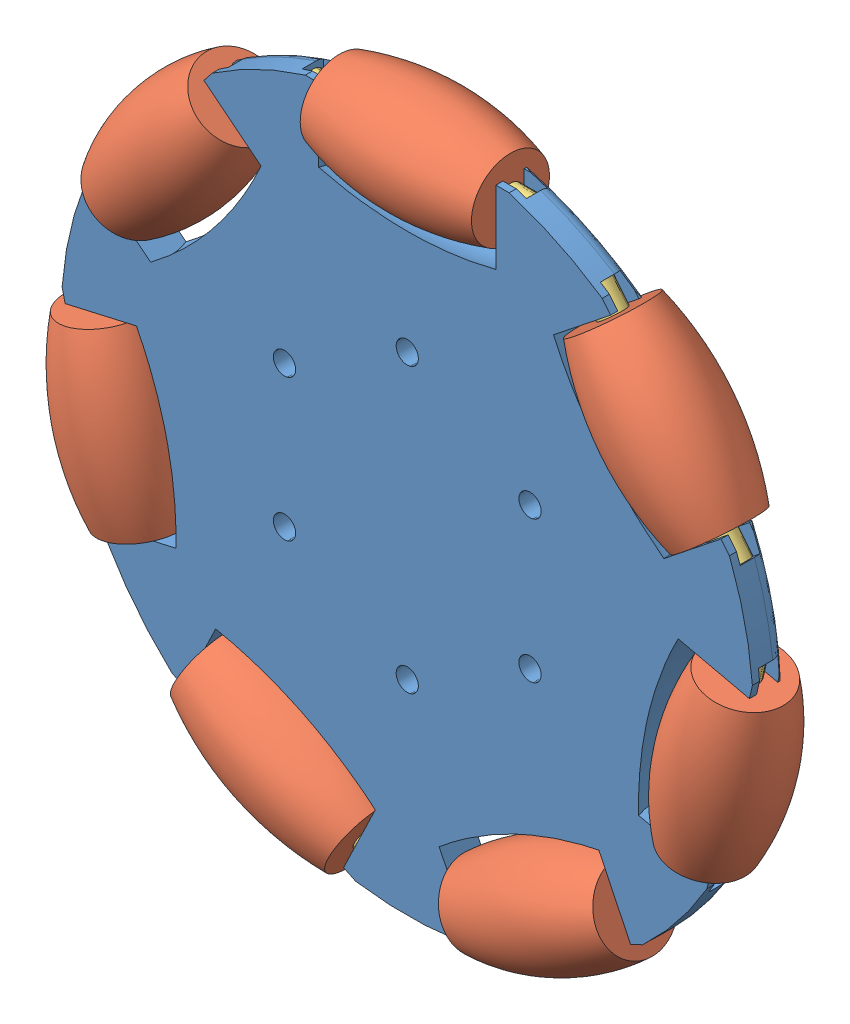
SolidWorks assembly OmniRueda, configuration Default. Lengths in mm.
Overall size (171.23 164.9 32.77).
15 component instances, 3 part files, 21 mates.
Components (placement in the parent):
- base1-1: base1 [Default] at (21.7624 30.7176 48.3759) size (155.19 151.79 15.2)
- tambor-1: tambor [Default] at (21.7309 100.0125 48.3759) size (38.41 23.31 23.31)
- tambor-2: tambor [Default] at (75.8785 73.9985 48.3759) x (0.62349 -0.781831 0) z (0.006132 0.00489 0.999969) size (38.41 23.31 23.31)
- tambor-3: tambor [Default] at (-32.3241 74.0356 48.3759) x (0.62349 0.781831 0) z (-0.451651 0.36018 0.816261) size (38.41 23.31 23.31)
- tambor-4: tambor [Default] at (89.32 15.2982 48.3759) x (0.222521 0.974928 0) z (-0.021105 0.004817 0.999766) size (38.41 23.31 23.31)
- tambor-5: tambor [Default] at (-45.7853 15.2549 48.3759) x (0.222521 -0.974928 0) z (-0.760422 -0.173561 0.625808) size (38.41 23.31 23.31)
- tambor-6: tambor [Default] at (51.6132 -31.8186 48.3759) x (0.900969 0.433884 0) z (-0.125061 0.259692 0.957559) size (38.41 23.31 23.31)
- tambor-7: tambor [Default] at (-8.5258 -31.6079 48.3759) x (0.900969 -0.433884 0) z (0.089476 0.185799 0.978505) size (38.41 23.31 23.31)
- Part1-1: Part1 [Default] at (46.9251 100.0125 48.3759) x (0 -0.961459 -0.274948) z (-1 0 0) size (5.83 5.83 50.33)
- Part1-2: Part1 [Default] at (-16.7258 93.5952 48.3759) x (0.669349 -0.533788 -0.516762) z (-0.62349 -0.781831 0) size (5.83 5.83 50.33)
- Part1-3: Part1 [Default] at (91.628 54.2493 48.3759) x (-0.207776 -0.165696 0.964041) z (-0.62349 0.781831 0) size (5.83 5.83 50.33)
- Part1-4: Part1 [Default] at (94.9204 39.8354 48.3759) x (-0.649686 0.148286 0.7456) z (-0.222521 -0.974928 0) size (5.83 5.83 50.33)
- Part1-5: Part1 [Default] at (14.3725 -42.6351 48.3759) x (0.3295 0.684213 0.650602) z (-0.900969 0.433884 0) size (5.83 5.83 50.33)
- Part1-6: Part1 [Default] at (74.5043 -20.7948 48.3759) x (-0.412763 0.857111 0.308201) z (-0.900969 -0.433884 0) size (5.83 5.83 50.33)
- Part1-7: Part1 [Default] at (-40.1946 -9.2394 48.3759) x (0.950484 0.216942 0.222521) z (-0.222521 0.974928 0) size (5.83 5.83 50.33)
Mates (geometry in assembly coordinates):
- Coincident3: coincident anti-aligned: circle of base1-1; cylinder of tambor-1 through (40.9362 100.0125 48.3759) axis (-1 0 0) radius 2.9139
- Coincident4: coincident anti-aligned: circle of base1-1; cylinder of tambor-2 through (87.8528 58.9832 48.3759) axis (-0.62349 0.781831 0) radius 2.9139
- Coincident5: coincident anti-aligned: circle of base1-1; cylinder of tambor-3 through (-20.3498 89.0509 48.3759) axis (-0.62349 -0.781831 0) radius 2.9139
- Coincident6: coincident aligned: circle of base1-1; cylinder of tambor-5 through (-41.5117 -3.4689 48.3759) axis (-0.222521 0.974928 0) radius 2.9139
- Coincident7: coincident aligned: circle of base1-1; cylinder of tambor-7 through (8.7776 -39.9408 48.3759) axis (-0.900969 0.433884 0) radius 2.9139
- Coincident8: coincident aligned: circle of base1-1; cylinder of tambor-6 through (68.9165 -23.4857 48.3759) axis (-0.900969 -0.433884 0) radius 2.9139
- Coincident9: coincident aligned: circle of base1-1; cylinder of tambor-4 through (93.5936 34.022 48.3759) axis (-0.222521 -0.974928 0) radius 2.9139
- Coincident12: coincident aligned: circle of base1-1; cylinder of Part1-1 through (-3.406 100.0125 48.3759) axis (1 0 0) radius 2.9139
- Coincident13: coincident anti-aligned: circle of base1-1; circle of Part1-1
- Concentric1: concentric anti-aligned: cylinder of tambor-3 through (-20.3498 89.0509 48.3759) axis (-0.62349 -0.781831 0) radius 2.9139; cylinder of Part1-2 through (-48.1068 54.2448 48.3759) axis (0.62349 0.781831 0) radius 2.9139
- Coincident14: coincident anti-aligned: circle of base1-1; circle of Part1-2
- Concentric2: concentric anti-aligned: cylinder of tambor-2 through (87.8528 58.9832 48.3759) axis (-0.62349 0.781831 0) radius 2.9139; cylinder of Part1-3 through (60.2471 93.5997 48.3759) axis (0.62349 -0.781831 0) radius 2.9139
- Coincident15: coincident anti-aligned: circle of base1-1; circle of Part1-3
- Concentric3: concentric anti-aligned: cylinder of base1-1 through (94.9204 39.8354 48.3759) axis (-0.222521 -0.974928 0) radius 2.9139; cylinder of Part1-4 through (83.7207 -9.2338 48.3759) axis (0.222521 0.974928 0) radius 2.9139
- Coincident16: coincident aligned: circle of base1-1; circle of Part1-4
- Concentric4: concentric anti-aligned: cylinder of base1-1 through (74.5043 -20.7948 48.3759) axis (-0.900969 -0.433884 0) radius 2.9139; cylinder of Part1-6 through (29.1575 -42.6326 48.3759) axis (0.900969 0.433884 0) radius 2.9139
- Coincident18: coincident aligned: circle of base1-1; circle of Part1-6
- Concentric5: concentric anti-aligned: cylinder of base1-1 through (14.3725 -42.6351 48.3759) axis (-0.900969 0.433884 0) radius 2.9139; cylinder of Part1-5 through (-30.9743 -20.7973 48.3759) axis (0.900969 -0.433884 0) radius 2.9139
- Coincident19: coincident aligned: circle of base1-1; circle of Part1-5
- Concentric6: concentric anti-aligned: cylinder of base1-1 through (-40.1946 -9.2394 48.3759) axis (-0.222521 0.974928 0) radius 2.9139; cylinder of Part1-7 through (-51.3943 39.8298 48.3759) axis (0.222521 -0.974928 0) radius 2.9139
- Coincident20: coincident aligned: circle of base1-1; circle of Part1-7
